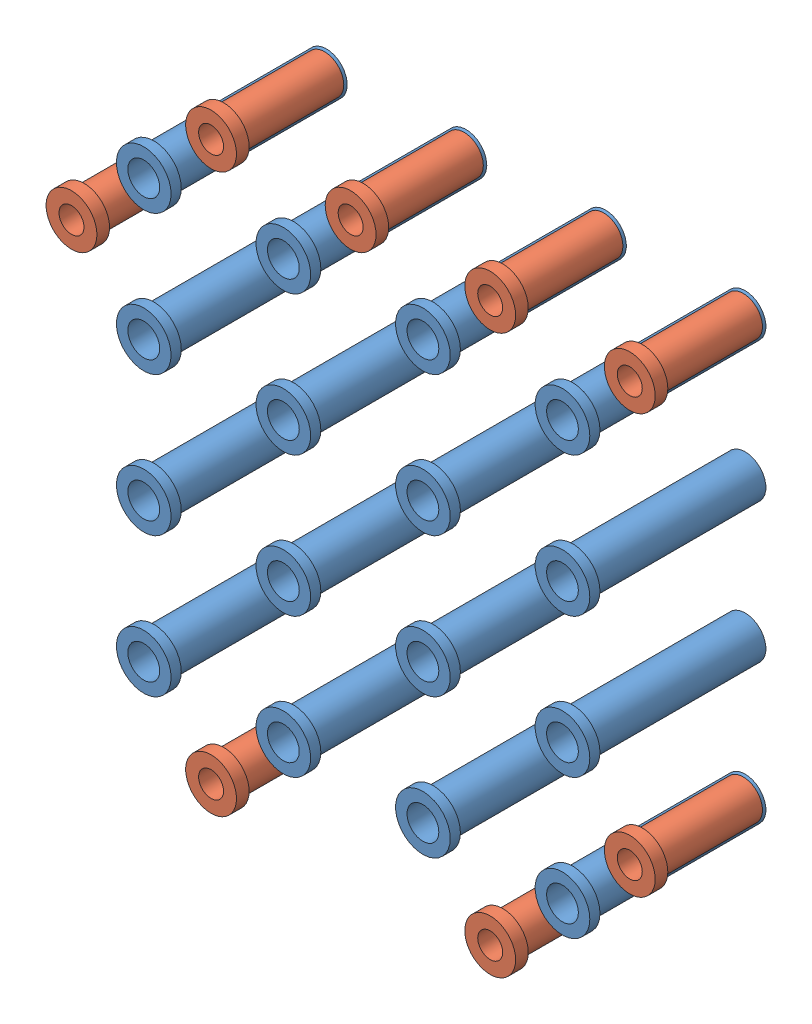
SolidWorks assembly SL10.4x4.pin-sockets, configuration Default. Lengths in mm.
Overall size (27.7 27.7 6.74).
25 component instances, 3 part files, 2 mates.
Components (placement in the parent):
- pin-socket.ED5008-1: pin-socket.ED5008 [Default] at (6.23 6.23 0) x (1 0 0) z (0 0 -1) size (1.99 1.99 6.65)
- pin-socket.ED5044-1: pin-socket.ED5044 [Default] at (24.01 24.01 0) x (1 0 0) z (0 0 -1) size (1.85 1.85 4.13)
- SL10.4x4.2D-1: SL10.4x4.2D [Default] at origin size (27.7 27.7 0) (hidden)
- pin-socket.ED5008-2: pin-socket.ED5008 [Default] at (6.23 11.31 0) x (1 0 0) z (0 0 -1) size (1.99 1.99 6.65)
- pin-socket.ED5008-3: pin-socket.ED5008 [Default] at (6.23 16.39 0) x (1 0 0) z (0 0 -1) size (1.99 1.99 6.65)
- pin-socket.ED5008-4: pin-socket.ED5008 [Default] at (6.23 21.47 0) x (1 0 0) z (0 0 -1) size (1.99 1.99 6.65)
- pin-socket.ED5008-5: pin-socket.ED5008 [Default] at (11.31 6.23 0) x (1 0 0) z (0 0 -1) size (1.99 1.99 6.65)
- pin-socket.ED5008-6: pin-socket.ED5008 [Default] at (11.31 11.31 0) x (1 0 0) z (0 0 -1) size (1.99 1.99 6.65)
- pin-socket.ED5008-7: pin-socket.ED5008 [Default] at (11.31 16.39 0) x (1 0 0) z (0 0 -1) size (1.99 1.99 6.65)
- pin-socket.ED5008-8: pin-socket.ED5008 [Default] at (11.31 21.47 0) x (1 0 0) z (0 0 -1) size (1.99 1.99 6.65)
- pin-socket.ED5008-9: pin-socket.ED5008 [Default] at (16.39 6.23 0) x (1 0 0) z (0 0 -1) size (1.99 1.99 6.65)
- pin-socket.ED5008-10: pin-socket.ED5008 [Default] at (16.39 11.31 0) x (1 0 0) z (0 0 -1) size (1.99 1.99 6.65)
- pin-socket.ED5008-11: pin-socket.ED5008 [Default] at (16.39 16.39 0) x (1 0 0) z (0 0 -1) size (1.99 1.99 6.65)
- pin-socket.ED5008-12: pin-socket.ED5008 [Default] at (16.39 21.47 0) x (1 0 0) z (0 0 -1) size (1.99 1.99 6.65)
- pin-socket.ED5008-13: pin-socket.ED5008 [Default] at (21.47 6.23 0) x (1 0 0) z (0 0 -1) size (1.99 1.99 6.65)
- pin-socket.ED5008-14: pin-socket.ED5008 [Default] at (21.47 11.31 0) x (1 0 0) z (0 0 -1) size (1.99 1.99 6.65)
- pin-socket.ED5008-15: pin-socket.ED5008 [Default] at (21.47 16.39 0) x (1 0 0) z (0 0 -1) size (1.99 1.99 6.65)
- pin-socket.ED5008-16: pin-socket.ED5008 [Default] at (21.47 21.47 0) x (1 0 0) z (0 0 -1) size (1.99 1.99 6.65)
- pin-socket.ED5044-4: pin-socket.ED5044 [Default] at (24.01 8.77 0) x (1 0 0) z (0 0 -1) size (1.85 1.85 4.13)
- pin-socket.ED5044-6: pin-socket.ED5044 [Default] at (18.93 24.01 0) x (1 0 0) z (0 0 -1) size (1.85 1.85 4.13)
- pin-socket.ED5044-10: pin-socket.ED5044 [Default] at (18.93 3.69 0) x (1 0 0) z (0 0 -1) size (1.85 1.85 4.13)
- pin-socket.ED5044-11: pin-socket.ED5044 [Default] at (13.85 24.01 0) x (1 0 0) z (0 0 -1) size (1.85 1.85 4.13)
- pin-socket.ED5044-16: pin-socket.ED5044 [Default] at (8.77 24.01 0) x (1 0 0) z (0 0 -1) size (1.85 1.85 4.13)
- pin-socket.ED5044-20: pin-socket.ED5044 [Default] at (8.77 3.69 0) x (1 0 0) z (0 0 -1) size (1.85 1.85 4.13)
- pin-socket.ED5044-22: pin-socket.ED5044 [Default] at (3.69 18.93 0) x (1 0 0) z (0 0 -1) size (1.85 1.85 4.13)
Mates (geometry in assembly coordinates):
- Coincident1: coincident anti-aligned: plane of pin-socket.ED5008-1 through (6.23 6.23 0) normal (0 0 -1); plane of assembly through (0 0 0) normal (0 0 1)
- Coincident3: coincident anti-aligned: plane of pin-socket.ED5044-1 through (24.01 24.01 0) normal (0 0 -1); plane of assembly through (0 0 0) normal (0 0 1)
